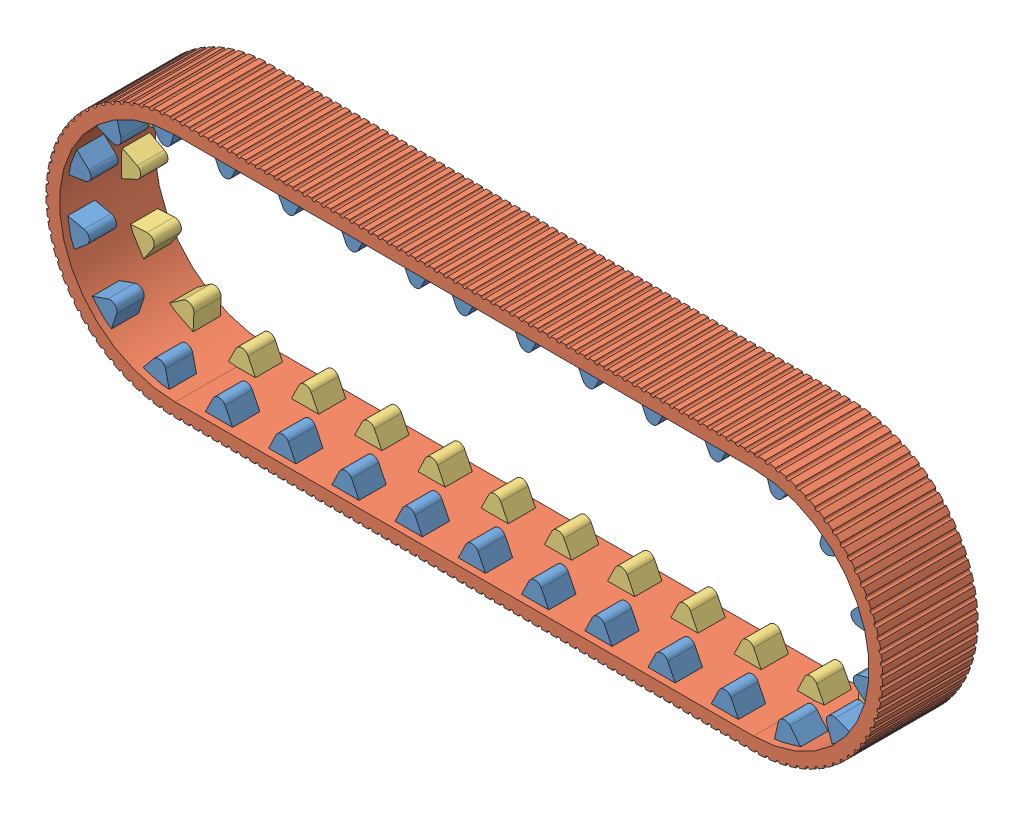
SolidWorks assembly Chaine, configuration Défaut. Lengths in mm.
Overall size (123 38 14).
61 component instances, 3 part files, 5 mates.
Components (placement in the parent):
- Maillon-Av-1: Maillon-Av [Défaut] at (-13.0064 14.628 6) x (-1 0 0) z (0 0 -1) size (4 3.69 4)
- Maillon-Av-2: Maillon-Av [Défaut] at (-22.301 14.628 6) x (-1 0 0) z (0 0 -1) size (4 3.69 4)
- Maillon-Av-3: Maillon-Av [Défaut] at (-31.5955 14.628 6) x (-1 0 0) z (0 0 -1) size (4 3.69 4)
- Maillon-Av-4: Maillon-Av [Défaut] at (-40.8901 14.628 6) x (-1 0 0) z (0 0 -1) size (4 3.69 4)
- Maillon-Av-5: Maillon-Av [Défaut] at (-47.2851 14.8049 6) x (-0.985389 -0.17032 0) z (0 0 -1) size (4 3.69 4)
- Maillon-Av-6: Maillon-Av [Défaut] at (-47.6289 15.6732 6) x (-0.751995 -0.659169 0) z (0 0 -1) size (4 3.69 4)
- Maillon-Av-7: Maillon-Av [Défaut] at (-48.3751 16.2348 6) x (-0.297932 -0.954587 0) z (0 0 -1) size (4 3.69 4)
- Maillon-Av-8: Maillon-Av [Défaut] at (-49.3047 16.3249 6) x (0.243558 -0.969886 0) z (0 0 -1) size (4 3.69 4)
- Maillon-Av-9: Maillon-Av [Défaut] at (-50.1448 15.9171 6) x (0.713577 -0.700576 0) z (0 0 -1) size (4 3.69 4)
- Maillon-Av-10: Maillon-Av [Défaut] at (-50.649 15.131 6) x (0.9742 -0.225686 0) z (0 0 -1) size (4 3.69 4)
- Maillon-Av-11: Maillon-Av [Défaut] at (-45.2881 14.628 6) x (1 0 0) z (0 0 -1) size (4 3.69 4)
- Maillon-Av-12: Maillon-Av [Défaut] at (-35.9935 14.628 6) x (1 0 0) z (0 0 -1) size (4 3.69 4)
- Maillon-Av-13: Maillon-Av [Défaut] at (-26.699 14.628 6) x (1 0 0) z (0 0 -1) size (4 3.69 4)
- Maillon-Av-14: Maillon-Av [Défaut] at (-17.4044 14.628 6) x (1 0 0) z (0 0 -1) size (4 3.69 4)
- Maillon-Av-15: Maillon-Av [Défaut] at (-8.1099 14.628 6) x (1 0 0) z (0 0 -1) size (4 3.69 4)
- Maillon-Av-16: Maillon-Av [Défaut] at (1.1847 14.628 6) x (1 0 0) z (0 0 -1) size (4 3.69 4)
- Maillon-Av-17: Maillon-Av [Défaut] at (10.4792 14.628 6) x (1 0 0) z (0 0 -1) size (4 3.69 4)
- Maillon-Av-18: Maillon-Av [Défaut] at (19.7738 14.628 6) x (1 0 0) z (0 0 -1) size (4 3.69 4)
- Maillon-Av-19: Maillon-Av [Défaut] at (29.0683 14.628 6) x (1 0 0) z (0 0 -1) size (4 3.69 4)
- Maillon-Av-20: Maillon-Av [Défaut] at (34.3015 14.3325 6) x (0.971181 0.238342 0) z (0 0 -1) size (4 3.69 4)
- Maillon-Av-21: Maillon-Av [Défaut] at (34.7048 13.4902 6) x (0.704401 0.709802 0) z (0 0 -1) size (4 3.69 4)
- Pièce2^Chaine-1: Pièce2^Chaine [Défaut] at origin size (123 38 14) (virtual)
- Maillon-Ar-1: Maillon-Ar [Défaut] at (-21.0919 14.628 -10) size (4 3.69 4)
- Maillon-Ar-2: Maillon-Ar [Défaut] at (-30.3855 14.628 -10) size (4 3.69 4)
- Maillon-Ar-3: Maillon-Ar [Défaut] at (-39.6792 14.628 -10) size (4 3.69 4)
- Maillon-Ar-4: Maillon-Ar [Défaut] at (-48.9649 14.6263 -10) x (1 0.000462 0) z (0 0 1) size (4 3.69 4)
- Maillon-Ar-5: Maillon-Ar [Défaut] at (-50.5014 13.7807 -10) x (0.902415 0.430869 0) z (0 0 1) size (4 3.69 4)
- Maillon-Ar-6: Maillon-Ar [Défaut] at (-49.8393 13.1221 -10) x (0.545376 0.838192 0) z (0 0 1) size (4 3.69 4)
- Maillon-Ar-7: Maillon-Ar [Défaut] at (-48.931 12.9054 -10) x (0.028329 0.999599 0) z (0 0 1) size (4 3.69 4)
- Maillon-Ar-8: Maillon-Ar [Défaut] at (-48.0429 13.1941 -10) x (-0.497028 0.867734 0) z (0 0 1) size (4 3.69 4)
- Maillon-Ar-9: Maillon-Ar [Défaut] at (-47.4356 13.9035 -10) x (-0.876563 0.481287 0) z (0 0 1) size (4 3.69 4)
- Maillon-Ar-10: Maillon-Ar [Défaut] at (-46.311 14.6301 -10) x (-0.999941 0.010843 0) z (0 0 1) size (4 3.69 4)
- Maillon-Ar-11: Maillon-Ar [Défaut] at (-37.2017 14.628 -10) x (-1 0 0) z (0 0 1) size (4 3.69 4)
- Maillon-Ar-12: Maillon-Ar [Défaut] at (-27.9081 14.628 -10) x (-1 0 0) z (0 0 1) size (4 3.69 4)
- Maillon-Ar-13: Maillon-Ar [Défaut] at (-18.6144 14.628 -10) x (-1 0 0) z (0 0 1) size (4 3.69 4)
- Maillon-Ar-14: Maillon-Ar [Défaut] at (-9.3208 14.628 -10) x (-1 0 0) z (0 0 1) size (4 3.69 4)
- Maillon-Ar-15: Maillon-Ar [Défaut] at (-0.0272 14.628 -10) x (-1 0 0) z (0 0 1) size (4 3.69 4)
- Maillon-Ar-16: Maillon-Ar [Défaut] at (9.2665 14.628 -10) x (-1 0 0) z (0 0 1) size (4 3.69 4)
- Maillon-Ar-17: Maillon-Ar [Défaut] at (18.5601 14.628 -10) x (-1 0 0) z (0 0 1) size (4 3.69 4)
- Maillon-Ar-18: Maillon-Ar [Défaut] at (27.8537 14.628 -10) x (-1 0 0) z (0 0 1) size (4 3.69 4)
- Maillon-Ar-19: Maillon-Ar [Défaut] at (36.8925 14.6818 -10) x (-0.999888 -0.014968 0) z (0 0 1) size (4 3.69 4)
- Maillon-Ar-20: Maillon-Ar [Défaut] at (37.4392 15.5772 -10) x (-0.87048 -0.492203 0) z (0 0 1) size (4 3.69 4)
- Maillon-Ar-21: Maillon-Ar [Défaut] at (36.7332 16.1884 -10) x (-0.486145 -0.873878 0) z (0 0 1) size (4 3.69 4)
- Maillon-Ar-22: Maillon-Ar [Défaut] at (35.8121 16.3418 -10) x (0.040819 -0.999167 0) z (0 0 1) size (4 3.69 4)
- Maillon-Av-22: Maillon-Av [Défaut] at (35.4882 12.9817 6) x (0.230918 0.972973 0) z (0 0 -1) size (4 3.69 4)
- Maillon-Ar-23: Maillon-Ar [Défaut] at (34.9461 15.9924 -10) x (0.555808 -0.831311 0) z (0 0 1) size (4 3.69 4)
- Maillon-Ar-24: Maillon-Ar [Défaut] at (34.3893 15.2428 -10) x (0.907729 -0.419558 0) z (0 0 1) size (4 3.69 4)
- Maillon-Ar-25: Maillon-Ar [Défaut] at (32.3202 14.628 -10) x (1 -0.000011 0) z (0 0 1) size (4 3.69 4)
- Maillon-Ar-26: Maillon-Ar [Défaut] at (23.0267 14.628 -10) size (4 3.69 4)
- Maillon-Ar-27: Maillon-Ar [Défaut] at (13.7331 14.628 -10) size (4 3.69 4)
- Maillon-Ar-28: Maillon-Ar [Défaut] at (4.4395 14.628 -10) size (4 3.69 4)
- Maillon-Ar-29: Maillon-Ar [Défaut] at (-4.8542 14.628 -10) size (4 3.69 4)
- Maillon-Ar-30: Maillon-Ar [Défaut] at (-14.1478 14.628 -10) size (4 3.69 4)
- Maillon-Av-23: Maillon-Av [Défaut] at (36.4218 12.9564 6) x (-0.310327 0.95063 0) z (0 0 -1) size (4 3.69 4)
- Maillon-Av-24: Maillon-Av [Défaut] at (37.2316 13.4216 6) x (-0.760508 0.649328 0) z (0 0 -1) size (4 3.69 4)
- Maillon-Av-25: Maillon-Av [Défaut] at (37.68 14.2408 6) x (-0.987522 0.157484 0) z (0 0 -1) size (4 3.69 4)
- Maillon-Av-26: Maillon-Av [Défaut] at (31.1091 14.628 6) x (-1 0 0) z (0 0 -1) size (4 3.69 4)
- Maillon-Av-27: Maillon-Av [Défaut] at (21.8145 14.628 6) x (-1 0 0) z (0 0 -1) size (4 3.69 4)
- Maillon-Av-28: Maillon-Av [Défaut] at (12.52 14.628 6) x (-1 0 0) z (0 0 -1) size (4 3.69 4)
- Maillon-Av-29: Maillon-Av [Défaut] at (3.2254 14.628 6) x (-1 0 0) z (0 0 -1) size (4 3.69 4)
- Maillon-Av-30: Maillon-Av [Défaut] at (-6.0691 14.628 6) x (-1 0 0) z (0 0 -1) size (4 3.69 4)
Mates (geometry in assembly coordinates):
- Sur place1: in place: plane of Pièce2^Chaine-1 through (0 0 0) normal (0 0 1); moOrthogonalPlaneRef_w of Pièce2^Chaine-1 through (0 0 0) normal (0 1 0); plane of Pièce2^Chaine-1 through (0 0 0) normal (1 0 0); unknown of Pièce2^Chaine-1
- Coïncidente1: coincident aligned: 
- Coïncidente2: coincident aligned: plane of Pièce2^Chaine-1 through (0 0 0) normal (0 1 0)
- Coïncidente3: coincident anti-aligned: plane of Pièce2^Chaine-1 through (0 0 0) normal (1 0 0)
- Distance2: distance = 4.65 mm: line of Maillon-Av-3 through (-31.3177 31.628 4) axis (0 0 -1); line of Maillon-Ar-2 through (-26.6677 31.628 -8) axis (0 0 1)
